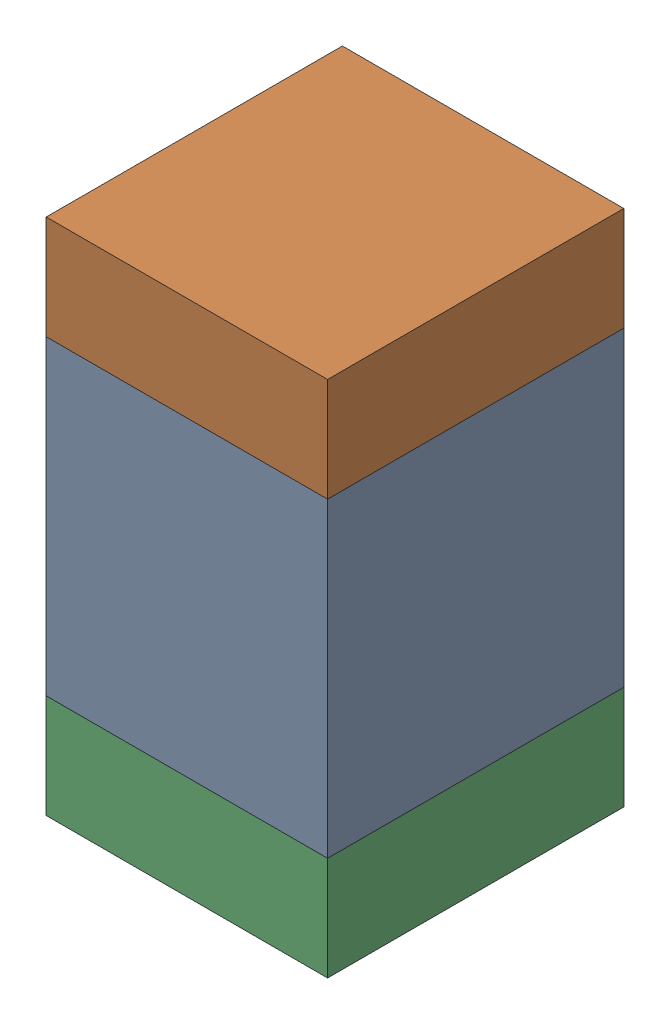
SolidWorks assembly C426PCB, configuration Default. Lengths in mm.
Overall size (0.95 1.75 1).
6 component instances, 2 part files, 0 mates.
Components (placement in the parent):
- 761616384-1: 761616384 [Default] at (139.2 104.6 -2.6638) size (0.95 1.05 1)
  - Extruded_5-1: Extruded_5 [Default] at origin size (0.95 1.05 1)
- 761616520-1: 761616520 [Default] at (139.2 105.3 -2.6638) size (0.95 0.35 1)
  - Extruded_6-1: Extruded_6 [Default] at origin size (0.95 0.35 1)
- 761616520-2: 761616520 [Default] at (139.2 103.9 -2.6638) size (0.95 0.35 1)
  - Extruded_6-1: Extruded_6 [Default] at origin size (0.95 0.35 1)
